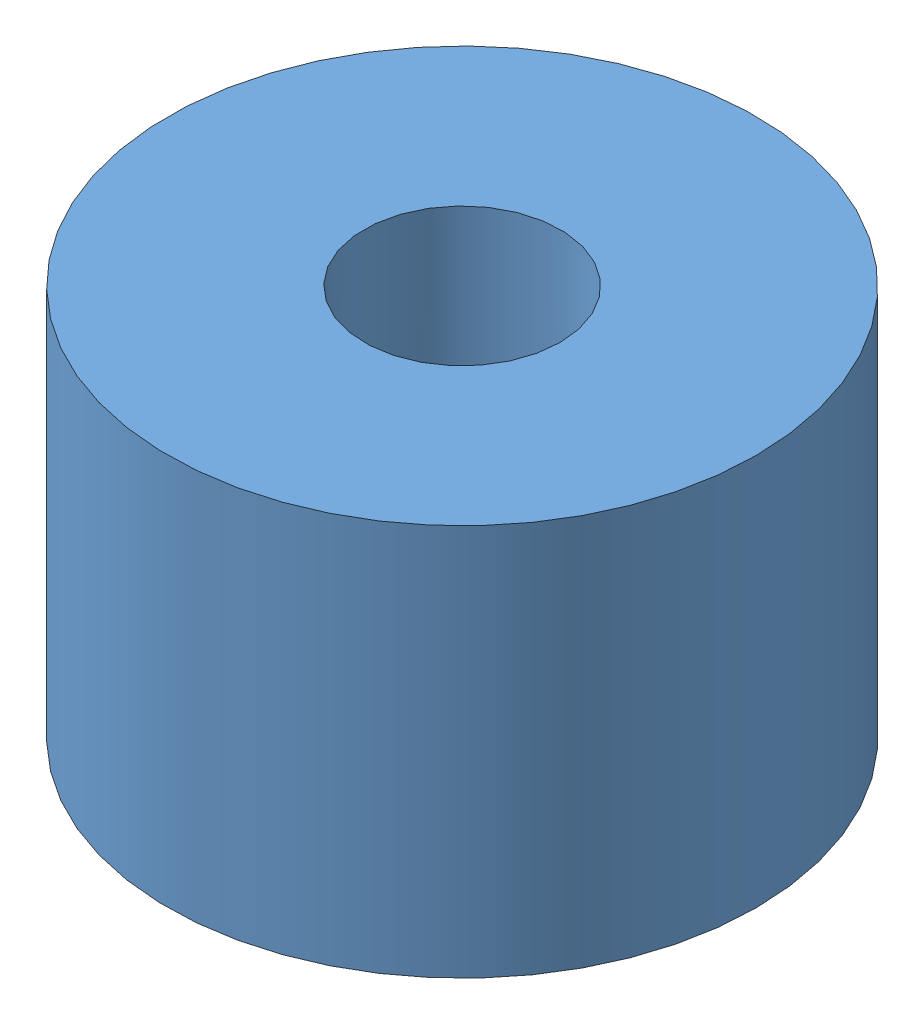
SolidWorks assembly Lens_coil_single, configuration Default. Lengths in mm.
Overall size (38.1 50.35 38.1).
2 component instances, 2 part files, 1 mates.
Components (placement in the parent):
- Single_piece_coil-1: Single_piece_coil [Default] at (-9.8468 -7.0277 9.9705) size (38.1 50.35 38.1)
- Coil-2: Coil [Default] at (-9.8468 -14.9512 9.9705) x (-0.99926 0 0.038452) z (-0.038452 0 -0.99926) size (28.57 22.68 28.57)
Mates (geometry in assembly coordinates):
- Distance2: distance = 0 mm: line of Coil-2 through (-9.8468 -14.9512 9.9705) axis (0 1 0); line of Single_piece_coil-1 through (-9.8468 -26.2925 9.9705) axis (0 1 0)
